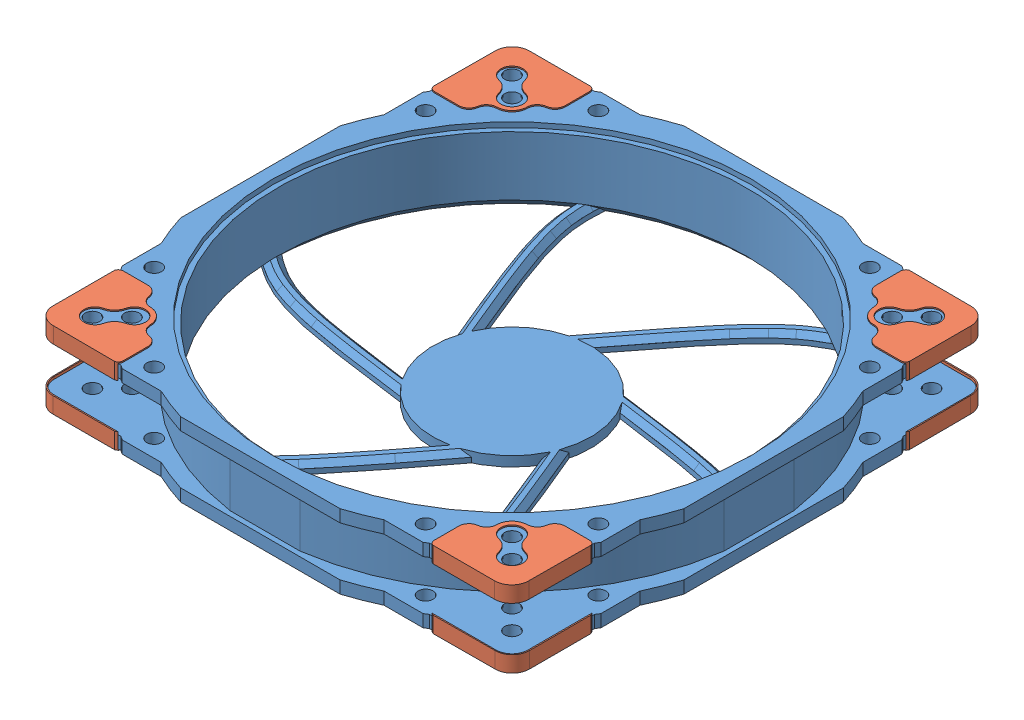
SolidWorks assembly NF-A20-Caase, configuration Standard. Lengths in mm.
Overall size (204 31 204).
9 component instances, 2 part files, 27 mates.
Components (placement in the parent):
- NF-A20-Case-1: NF-A20-Case [Standard] at (-102 -30.5 -102) size (204 30 204)
- NF-A20-Rubber-Edge-1: NF-A20-Rubber-Edge [Standard] at (-101.5 -0.5 -101.5) x (0 0 1) z (1 0 0) size (33.51 6.5 33.5)
- NF-A20-Rubber-Edge-2: NF-A20-Rubber-Edge [Standard] at (-101.5 -0.5 -102.5) x (1 0 0) z (0 0 -1) size (33.51 6.5 33.5)
- NF-A20-Rubber-Edge-3: NF-A20-Rubber-Edge [Standard] at (-102.5 -0.5 -101.5) x (-1 0 0) z (0 0 1) size (33.51 6.5 33.5)
- NF-A20-Rubber-Edge-4: NF-A20-Rubber-Edge [Standard] at (-102.5 -0.5 -102.5) x (0 0 -1) z (-1 0 0) size (33.51 6.5 33.5)
- NF-A20-Rubber-Edge-5: NF-A20-Rubber-Edge [Standard] at (-102.5 -30.5 -102.5) x (-1 0 0) z (0 0 -1) size (33.51 6.5 33.5)
- NF-A20-Rubber-Edge-6: NF-A20-Rubber-Edge [Standard] at (-101.5 -30.5 -102.5) x (0 0 -1) z (1 0 0) size (33.51 6.5 33.5)
- NF-A20-Rubber-Edge-7: NF-A20-Rubber-Edge [Standard] at (-102.5 -30.5 -101.5) x (0 0 1) z (-1 0 0) size (33.51 6.5 33.5)
- NF-A20-Rubber-Edge-8: NF-A20-Rubber-Edge [Standard] at (-101.5 -30.5 -101.5) size (33.51 6.5 33.5)
Mates (geometry in assembly coordinates):
- Deckungsgleich1: coincident anti-aligned: plane of NF-A20-Case-1 through (-102 -0.5 -102) normal (0 1 0); plane of NF-A20-Rubber-Edge-8 through (-181.2472 -0.5 -181.25) normal (0 -1 0)
- Deckungsgleich2: coincident anti-aligned: plane of NF-A20-Case-1 through (-102 -0.5 -102) normal (0 1 0); plane of NF-A20-Rubber-Edge-7 through (-22.75 -0.5 -181.2472) normal (0 -1 0)
- Deckungsgleich3: coincident anti-aligned: plane of NF-A20-Case-1 through (-102 -0.5 -102) normal (0 1 0); plane of NF-A20-Rubber-Edge-5 through (-22.7528 -0.5 -22.75) normal (0 -1 0)
- Deckungsgleich4: coincident anti-aligned: plane of NF-A20-Case-1 through (-102 -0.5 -102) normal (0 1 0); plane of NF-A20-Rubber-Edge-6 through (-181.25 -0.5 -22.7528) normal (0 -1 0)
- Deckungsgleich5: coincident anti-aligned: plane of NF-A20-Case-1 through (-43.3821 -30.5 -112.2216) normal (0 -1 0); plane of NF-A20-Rubber-Edge-2 through (-181.2472 -30.5 -22.75) normal (0 1 0)
- Deckungsgleich6: coincident anti-aligned: plane of NF-A20-Case-1 through (-43.3821 -30.5 -112.2216) normal (0 -1 0); plane of NF-A20-Rubber-Edge-4 through (-22.75 -30.5 -22.7528) normal (0 1 0)
- Deckungsgleich7: coincident anti-aligned: plane of NF-A20-Case-1 through (-43.3821 -30.5 -112.2216) normal (0 -1 0); plane of NF-A20-Rubber-Edge-3 through (-22.7528 -30.5 -181.25) normal (0 1 0)
- Deckungsgleich8: coincident anti-aligned: plane of NF-A20-Case-1 through (-43.3821 -30.5 -112.2216) normal (0 -1 0); plane of NF-A20-Rubber-Edge-1 through (-181.25 -30.5 -181.2472) normal (0 1 0)
- Deckungsgleich9: coincident anti-aligned: plane of NF-A20-Case-1 through (-39.502 -30.5 -6) normal (0 0 1); plane of NF-A20-Rubber-Edge-5 through (-38.7496 -30.5 -6) normal (0 0 -1)
- Deckungsgleich10: coincident anti-aligned: plane of NF-A20-Case-1 through (-6 -30.5 -12) normal (1 0 0); plane of NF-A20-Rubber-Edge-5 through (-6 -30.5 -12.5) normal (-1 0 0)
- Deckungsgleich11: coincident anti-aligned: plane of NF-A20-Case-1 through (-12 -30.5 -198) normal (0 0 -1); plane of NF-A20-Rubber-Edge-7 through (-12.5 -30.5 -198) normal (0 0 1)
- Deckungsgleich12: coincident anti-aligned: plane of NF-A20-Case-1 through (-6 -30.5 -164.498) normal (1 0 0); plane of NF-A20-Rubber-Edge-7 through (-6 -30.5 -165.2504) normal (-1 0 0)
- Deckungsgleich13: coincident anti-aligned: plane of NF-A20-Case-1 through (-164.498 -30.5 -198) normal (0 0 -1); plane of NF-A20-Rubber-Edge-8 through (-165.2504 -30.5 -198) normal (0 0 1)
- Deckungsgleich14: coincident anti-aligned: plane of NF-A20-Case-1 through (-198 -30.5 -192) normal (-1 0 0); plane of NF-A20-Rubber-Edge-8 through (-198 -30.5 -191.5) normal (1 0 0)
- Deckungsgleich15: coincident anti-aligned: plane of NF-A20-Case-1 through (-192 -30.5 -6) normal (0 0 1); plane of NF-A20-Rubber-Edge-6 through (-191.5 -30.5 -6) normal (0 0 -1)
- Deckungsgleich16: coincident anti-aligned: plane of NF-A20-Case-1 through (-198 -30.5 -39.502) normal (-1 0 0); plane of NF-A20-Rubber-Edge-6 through (-198 -30.5 -38.7496) normal (1 0 0)
- Deckungsgleich17: coincident anti-aligned: plane of NF-A20-Case-1 through (-39.502 -30.5 -6) normal (0 0 1); plane of NF-A20-Rubber-Edge-4 through (-12.5 -0.5 -6) normal (0 0 -1)
- Deckungsgleich18: coincident anti-aligned: plane of NF-A20-Case-1 through (-6 -30.5 -12) normal (1 0 0); plane of NF-A20-Rubber-Edge-4 through (-6 -0.5 -38.7496) normal (-1 0 0)
- Deckungsgleich19: coincident anti-aligned: plane of NF-A20-Case-1 through (-6 -30.5 -164.498) normal (1 0 0); plane of NF-A20-Rubber-Edge-3 through (-6 -0.5 -191.5) normal (-1 0 0)
- Deckungsgleich20: coincident anti-aligned: plane of NF-A20-Case-1 through (-12 -30.5 -198) normal (0 0 -1); plane of NF-A20-Rubber-Edge-3 through (-38.7496 -0.5 -198) normal (0 0 1)
- Deckungsgleich21: coincident anti-aligned: plane of NF-A20-Case-1 through (-164.498 -30.5 -198) normal (0 0 -1); plane of NF-A20-Rubber-Edge-1 through (-191.5 -0.5 -198) normal (0 0 1)
- Deckungsgleich22: coincident anti-aligned: plane of NF-A20-Case-1 through (-198 -30.5 -192) normal (-1 0 0); plane of NF-A20-Rubber-Edge-1 through (-198 -0.5 -165.2504) normal (1 0 0)
- Deckungsgleich23: coincident anti-aligned: plane of NF-A20-Case-1 through (-192 -30.5 -6) normal (0 0 1); plane of NF-A20-Rubber-Edge-2 through (-165.2504 -0.5 -6) normal (0 0 -1)
- Deckungsgleich24: coincident anti-aligned: plane of NF-A20-Case-1 through (-198 -30.5 -39.502) normal (-1 0 0); plane of NF-A20-Rubber-Edge-2 through (-198 -0.5 -12.5) normal (1 0 0)
- Deckungsgleich25: coincident aligned: plane of NF-A20-Rubber-Edge-8 through (-181.7472 0 -181.75) normal (0 1 0); plane of assembly
- Deckungsgleich26: coincident aligned: plane of NF-A20-Case-1 through (0 -30.5 -69.6735) normal (1 0 0); plane of assembly
- Deckungsgleich27: coincident aligned: plane of NF-A20-Case-1 through (-134.3265 -30.5 0) normal (0 0 1); plane of assembly
